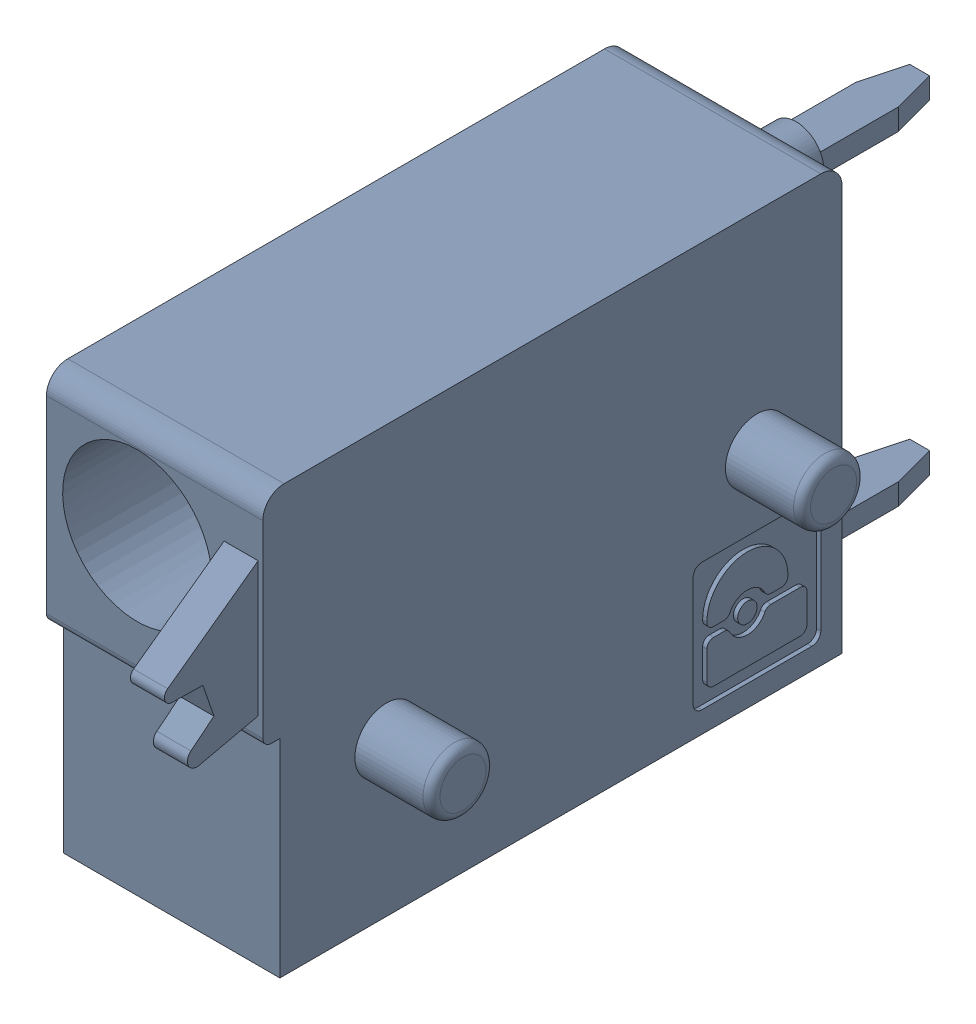
SolidWorks assembly J78, configuration Default. Lengths in mm.
Overall size (6.88 10 19.2).
2 component instances, 1 part files, 0 mates.
Components (placement in the parent):
- 1790348-1: 1790348 [Default] at (227.9651 -7.6199 0) x (0 1 0) z (1 0 0) size (10 19.2 6.88)
  - ffkds-v2-5.08-1: ffkds-v2-5.08 [Default] at (-23.7414 -38.158 -2.54) x (0 -1 0) z (0 0 1) size (19.2 10 6.88)
